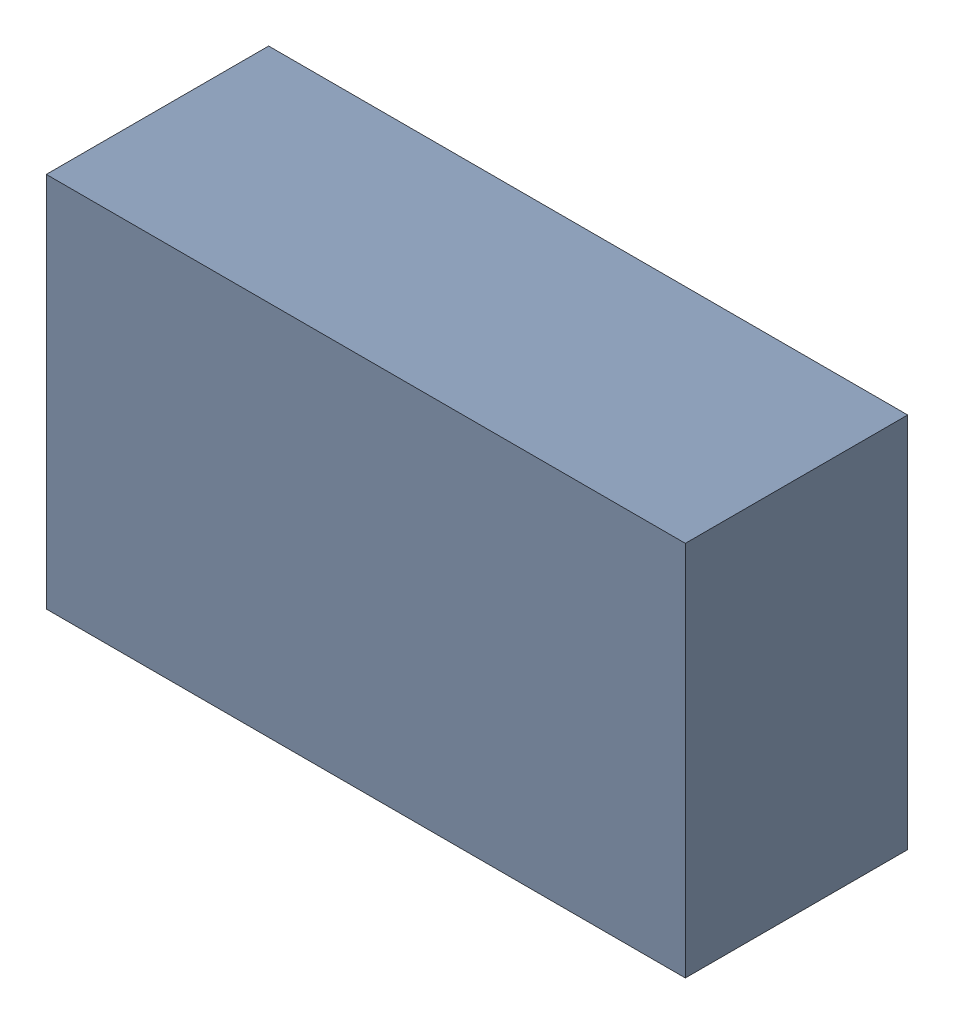
SolidWorks assembly 6327398080, configuration Default. Lengths in mm.
Overall size (0.73 0.43 0.25).
2 component instances, 1 part files, 0 mates.
Components (placement in the parent):
- 6701982208-1:  [Default] at (27.7 14.8 0) (suppressed, hidden)
- Extruded-17-1: Extruded-17 [Default] at origin size (0.73 0.43 0.25)
